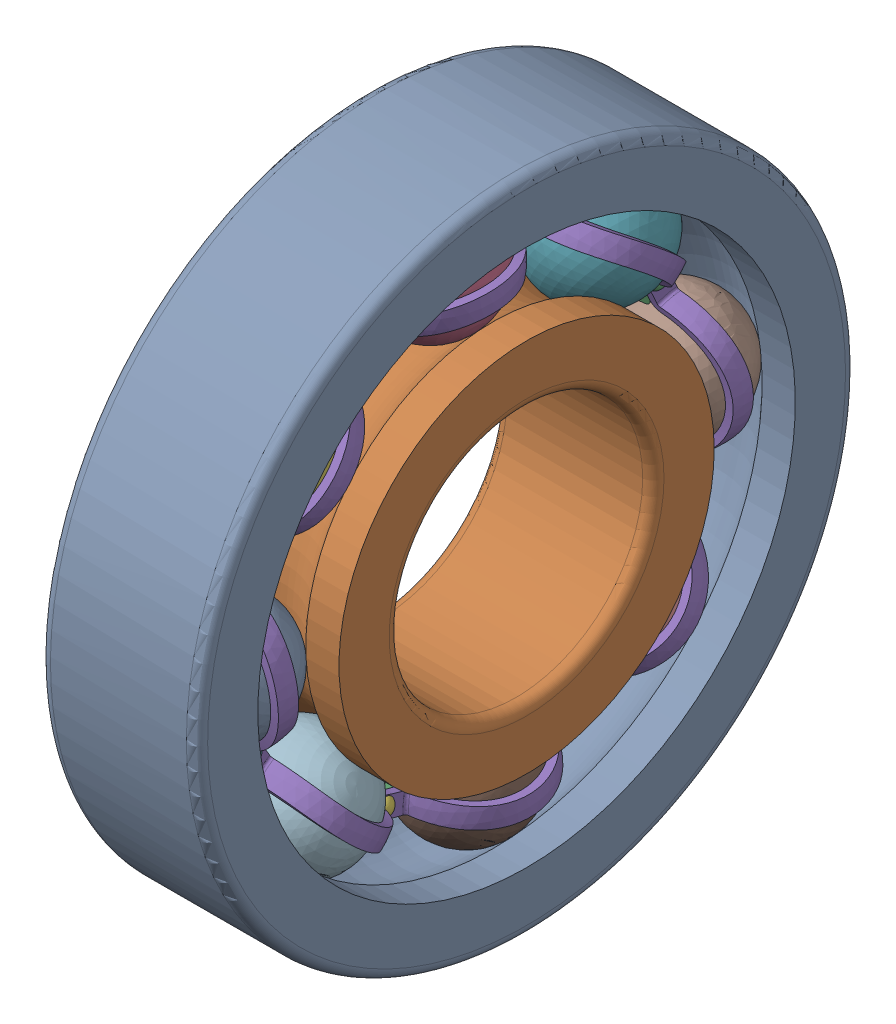
SolidWorks assembly ball_bearing, configuration Default. Lengths in mm.
Overall size (4.03 18.23 18.23).
20 component instances, 5 part files, 15 mates.
Components (placement in the parent):
- ball_bearing_outerRing-1: ball_bearing_outerRing [Default] at (-30.4245 -127.5639 49.4717) x (1 0 0) z (0 0.927062 0.374909) size (3.34 14 14)
- ball_bearing_innerRing-1: ball_bearing_innerRing [Default] at (-30.4245 -85.8966 -105.371) x (1 0 0) z (0 -0.052073 0.998643) size (3.34 7.97 7.97)
- ball_bearing_cage-1: ball_bearing_cage [Default] at (-30.338 -19.8057 -135.1344) x (1 0 0) z (0 -0.550603 0.834767) size (1.47 10.12 10.12)
- ball_bearing_ball-1: ball_bearing_ball [Default] at (-16.9384 -78.8275 -114.8388) x (-0.826423 0.553883 -0.10119) z (0.522065 0.821103 0.230733) size (2.58 2.58 2.58)
- ball_bearing_cage-2: ball_bearing_cage [Default] at (20.6644 -41.0482 132.5599) x (-1 0 0) z (0 -0.412058 -0.911158) size (1.47 10.12 10.12)
- ball_bearing_ball-2: ball_bearing_ball [Default] at (-132.3854 44.8027 -51.4615) x (0.197764 0.798121 0.569115) z (0.948377 -0.00894 -0.317019) size (2.58 2.58 2.58)
- ball_bearing_ball-5: ball_bearing_ball [Default] at (-16.9384 -79.9713 -118.3669) x (-0.826423 0.553883 -0.10119) z (0.522065 0.821103 0.230733) size (2.58 2.58 2.58)
- ball_bearing_ball-6: ball_bearing_ball [Default] at (-16.9384 -83.2749 -120.0529) x (-0.826423 0.553883 -0.10119) z (0.522065 0.821103 0.230733) size (2.58 2.58 2.58)
- ball_bearing_rivet-1: ball_bearing_rivet [Default] at (-30.4245 -86.4154 -93.0862) size (0.55 0.39 0.39)
- ball_bearing_ball-9: ball_bearing_ball [Default] at (-132.3854 -41.0463 54.0141) x (0.197764 -0.798121 -0.569115) z (0.948377 0.00894 0.317019) size (2.58 2.58 2.58)
- ball_bearing_ball-10: ball_bearing_ball [Default] at (-16.9384 82.5839 117.3914) x (-0.826423 -0.553883 0.10119) z (0.522065 -0.821103 -0.230733) size (2.58 2.58 2.58)
- ball_bearing_ball-11: ball_bearing_ball [Default] at (-16.9384 83.7278 120.9195) x (-0.826423 -0.553883 0.10119) z (0.522065 -0.821103 -0.230733) size (2.58 2.58 2.58)
- ball_bearing_ball-12: ball_bearing_ball [Default] at (-16.9384 87.0314 122.6055) x (-0.826423 -0.553883 0.10119) z (0.522065 -0.821103 -0.230733) size (2.58 2.58 2.58)
- ball_bearing_rivet-2: ball_bearing_rivet [Default] at (-30.4245 -127.2791 -3.0151) x (1 0 0) z (0 0.707107 0.707107) size (0.55 0.39 0.39)
- ball_bearing_rivet-3: ball_bearing_rivet [Default] at (-30.4245 -92.4843 89.5699) x (1 0 0) z (0 1 0) size (0.55 0.39 0.39)
- ball_bearing_rivet-4: ball_bearing_rivet [Default] at (-30.4245 -2.4131 130.4336) x (1 0 0) z (0 0.707107 -0.707107) size (0.55 0.39 0.39)
- ball_bearing_rivet-5: ball_bearing_rivet [Default] at (-30.4245 90.1718 95.6388) x (1 0 0) z (0 0 -1) size (0.55 0.39 0.39)
- ball_bearing_rivet-6: ball_bearing_rivet [Default] at (-30.4245 131.0356 5.5676) x (1 0 0) z (0 -0.707107 -0.707107) size (0.55 0.39 0.39)
- ball_bearing_rivet-7: ball_bearing_rivet [Default] at (-30.4245 96.2407 -87.0173) x (1 0 0) z (0 -1 0) size (0.55 0.39 0.39)
- ball_bearing_rivet-8: ball_bearing_rivet [Default] at (-30.4245 6.1696 -127.8811) x (1 0 0) z (0 -0.707107 0.707107) size (0.55 0.39 0.39)
Mates (geometry in assembly coordinates):
- Concentric1: concentric aligned: cylinder of ball_bearing_outerRing-1 through (-6.2162 1.8782 1.2763) axis (-1 0 0) radius 5.7075; cylinder of ball_bearing_innerRing-1 through (-7.4723 1.8782 1.2763) axis (-1 0 0) radius 3.9845
- Coincident1: coincident aligned: plane of ball_bearing_outerRing-1 through (-3.1677 5.4154 -4.7639) normal (1 0 0); plane of ball_bearing_innerRing-1 through (-3.1677 4.7926 1.4283) normal (1 0 0)
- Tangent1: tangent anti-aligned: torus of ball_bearing_outerRing-1; sphere of ball_bearing_ball-1
- Concentric2: concentric: sphere of ball_bearing_cage-1; sphere of ball_bearing_ball-1
- Concentric3: concentric: sphere of ball_bearing_ball-1; sphere of ball_bearing_cage-2
- Parallel2: parallel anti-aligned: plane of ball_bearing_cage-1 through (-4.8368 1.8782 1.2763) normal (1 0 0); plane of ball_bearing_cage-2 through (-4.8368 1.8782 1.2763) normal (-1 0 0)
- Tangent2: tangent anti-aligned: torus of ball_bearing_outerRing-1; sphere of ball_bearing_ball-2
- Concentric5: concentric: sphere of ball_bearing_cage-2; sphere of ball_bearing_ball-2
- Concentric6: concentric: sphere of ball_bearing_cage-1; sphere of ball_bearing_ball-2
- Concentric7: concentric: sphere of ball_bearing_cage-2; sphere of ball_bearing_ball-5
- Tangent3: tangent anti-aligned: torus of ball_bearing_outerRing-1; sphere of ball_bearing_ball-5
- Concentric8: concentric: sphere of ball_bearing_cage-2; sphere of ball_bearing_ball-6
- Tangent4: tangent anti-aligned: torus of ball_bearing_outerRing-1; sphere of ball_bearing_ball-6
- Coincident3: coincident anti-aligned: plane of ball_bearing_cage-1 through (-4.9983 1.8782 1.2763) normal (-1 0 0); plane of ball_bearing_rivet-1 through (-4.9983 6.298 3.509) normal (1 0 0)
- Concentric9: concentric aligned: cylinder of ball_bearing_cage-1 through (-6.2906 6.1946 3.4791) axis (1 0 0) radius 0.1077; cylinder of ball_bearing_rivet-1 through (-4.5596 6.1946 3.4791) axis (1 0 0) radius 0.1077
